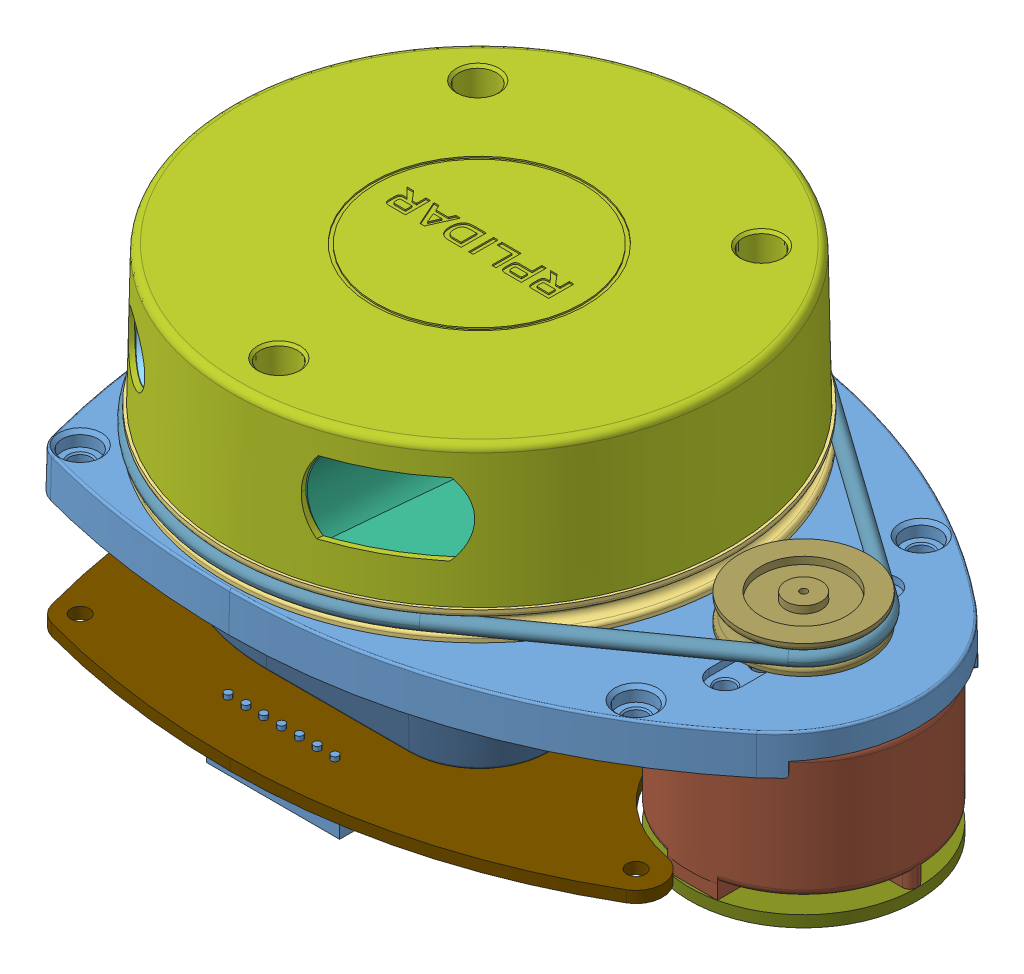
SolidWorks assembly LIDAR, configuration По умолчанию. Lengths in mm.
Overall size (102.81 52.61 71.78).
20 component instances, 20 part files, 29 mates.
Components (placement in the parent):
- 1-1: 1 [По умолчанию] at (0 -17 0) size (96.74 12.71 70.28)
- 2-1: 2 [По умолчанию] at (0 -15 0) x (1 0 0) z (0 -1 0) size (47 47 7.01)
- 3-1: 3 [По умолчанию] at (0 -13 0) x (0.00451 0 -0.99999) z (0.99999 0 0.00451) size (70.79 21.41 70.79)
- 4-1: 4 [По умолчанию] at (-25.1552 0 -6.8741) x (0.990886 0 -0.134705) z (0.134705 0 0.990886) size (6.5 6.5 21.2)
- 5-1: 5 [По умолчанию] at (0 -9 0) x (-0.99999 0 -0.00451) z (0.00451 0 -0.99999) size (15.26 18.52 21.56)
- 6-1: 6 [По умолчанию] at (0 -9 0) x (-0.99999 0 -0.00451) z (0.00451 0 -0.99999) size (22.09 18.86 24.76)
- 7-1: 7 [По умолчанию] at (0 9 0) x (0.99999 0 0.00451) z (0.00451 0 -0.99999) size (70 19.51 70)
- 8-1: 8 [По умолчанию] at (0 -26 0) x (0.987093 0 -0.160146) z (0.160146 0 0.987093) size (25 1.2 25)
- 9-1: 9 [По умолчанию] at (0 -27 0) size (55.5 1 57)
- 10-1: 10 [По умолчанию] at (0 -28 0) size (59.96 11.11 60.96)
- 11-1: 11 [По умолчанию] at (45.5 -36.5 0) x (0 0 -1) z (1 0 0) size (32 30.21 32.01)
- 12-1: 12 [По умолчанию] at (45.5 -14.5 0) x (0.135455 0 -0.990784) z (0.990784 0 0.135455) size (18 5.5 18)
- 13-1: 13 [По умолчанию] at (16.948 0 11.5766) x (0.136926 0.990581 0.000618) z (-0.00451 0 0.99999) size (14 14 11.5)
- 14-1: 14 [По умолчанию] at (0 -12.5 0) x (1 0 0) z (0 -1 0) size (90.89 71.78 2)
- 15-1: 15 [По умолчанию] at (24.11 -29.4 0) x (0 0 -1) z (0 -1 0) size (10.15 4.2 4.7)
- 16-1: 16 [По умолчанию] at (45.5 -40.1 0) x (-0.441218 0 -0.8974) z (0.8974 0 -0.441218) size (32 1.6 32)
- 17-1: 17 [По умолчанию] at (32.56 -41.8 0) x (0 0 1) z (0 -1 0) size (8.9 5.2 3.4)
- 19-1: 19 [По умолчанию] at (0 -36 0) x (1 0 0) z (0 0 -1) size (80.7 4.7 70)
- 20-1: 20 [По умолчанию] at (0 -37.6 27.1) x (0 -1 0) z (1 0 0) size (8.2 5 20)
- 22-1: 22 [По умолчанию] at (17.68 -37.7 0) x (0 0 1) z (1 0 0) size (8.8 4.7 4.36)
Mates (geometry in assembly coordinates):
- Концентричный1: concentric anti-aligned: cylinder of 19-1 through (-7.5 -35.6 27.75) axis (0 1 0) radius 0.5; cylinder of 20-1 through (-7.5 -35.6 27.75) axis (0 -1 0) radius 0.5
- Концентричный2: concentric anti-aligned: cylinder of 19-1 through (7.5 -35.6 27.75) axis (0 1 0) radius 0.5; cylinder of 20-1 through (7.5 -35.6 27.75) axis (0 -1 0) radius 0.5
- Совпадение1: coincident anti-aligned: plane of 19-1 through (-14 -35.6 23.3292) normal (0 -1 0); plane of 20-1 through (0 -35.6 27.1) normal (0 1 0)
- Совпадение7: coincident anti-aligned: plane of 19-1 through (0 -35.7 0) normal (0 -1 0); plane of 22-1 through (17.68 -35.7 0) normal (0 1 0)
- Совпадение8: coincident aligned: plane of 19-1 through (16 -35.7 -4.4) normal (-1 0 0); plane of 22-1 through (16 -40.4 -2.75) normal (-1 0 0)
- Совпадение9: coincident: line of 19-1 through (16 -35.7 4.4) axis (1 0 0); plane of 22-1 through (13.4155 -36 4.4) normal (0 0 1)
- Концентричный9: concentric aligned: cylinder of 1-1 through (45.5 -19 11) axis (0 1 0) radius 1.25; cylinder of 11-1 through (45.5 -23 11) axis (0 1 0) radius 1
- Концентричный10: concentric aligned: cylinder of 1-1 through (45.5 -19 -11) axis (0 1 0) radius 1.25; cylinder of 11-1 through (45.5 -23 -11) axis (0 1 0) radius 1
- Концентричный11: concentric anti-aligned: cylinder of 11-1 through (45.5 -38.5 0) axis (0 1 0) radius 3.5; cylinder of 16-1 through (45.5 -38.5 0) axis (0 -1 0) radius 3.75
- Совпадение10: coincident anti-aligned: plane of 11-1 through (45.5 -38.5 0) normal (0 -1 0); plane of 16-1 through (45.5 -38.5 0) normal (0 1 0)
- Совпадение11: coincident anti-aligned: plane of 1-1 through (0 -19 0) normal (0 -1 0); plane of 11-1 through (45.5 -19 0) normal (0 1 0)
- Concentric1: concentric anti-aligned: cylinder of 1-1 through (42 -17.7 -20) axis (0 -1 0) radius 1.5; cylinder of 19-1 through (42 -35.6 -20) axis (0 1 0) radius 1.3
- Concentric2: concentric anti-aligned: cylinder of 1-1 through (-28 -17.7 -28) axis (0 -1 0) radius 1.5; cylinder of 19-1 through (-28 -35.6 -28) axis (0 1 0) radius 1.3
- Distance1: distance = 15 mm anti-aligned: plane of 1-1 through (0 -21 62.2833) normal (0 -1 0); plane of 19-1 through (-14 -36 23.3292) normal (0 1 0)
- Lock11: lock: unknown of 1-1; unknown of 2-1
- Lock12: lock: unknown of 1-1; unknown of 3-1
- Lock13: lock: unknown of 1-1; unknown of 4-1
- Lock14: lock: unknown of 1-1; unknown of 5-1
- Lock15: lock: unknown of 1-1; unknown of 6-1
- Lock16: lock: unknown of 1-1; unknown of 7-1
- Lock17: lock: unknown of 1-1; unknown of 8-1
- Lock18: lock: unknown of 1-1; unknown of 9-1
- Lock20: lock: unknown of 1-1; unknown of 11-1
- Lock21: lock: unknown of 1-1; unknown of 12-1
- Lock22: lock: unknown of 1-1; unknown of 13-1
- Lock23: lock: unknown of 1-1; unknown of 14-1
- Lock25: lock: unknown of 1-1; unknown of 10-1
- Lock26: lock: unknown of 16-1; unknown of 17-1
- Lock27: lock: unknown of 10-1; unknown of 15-1
